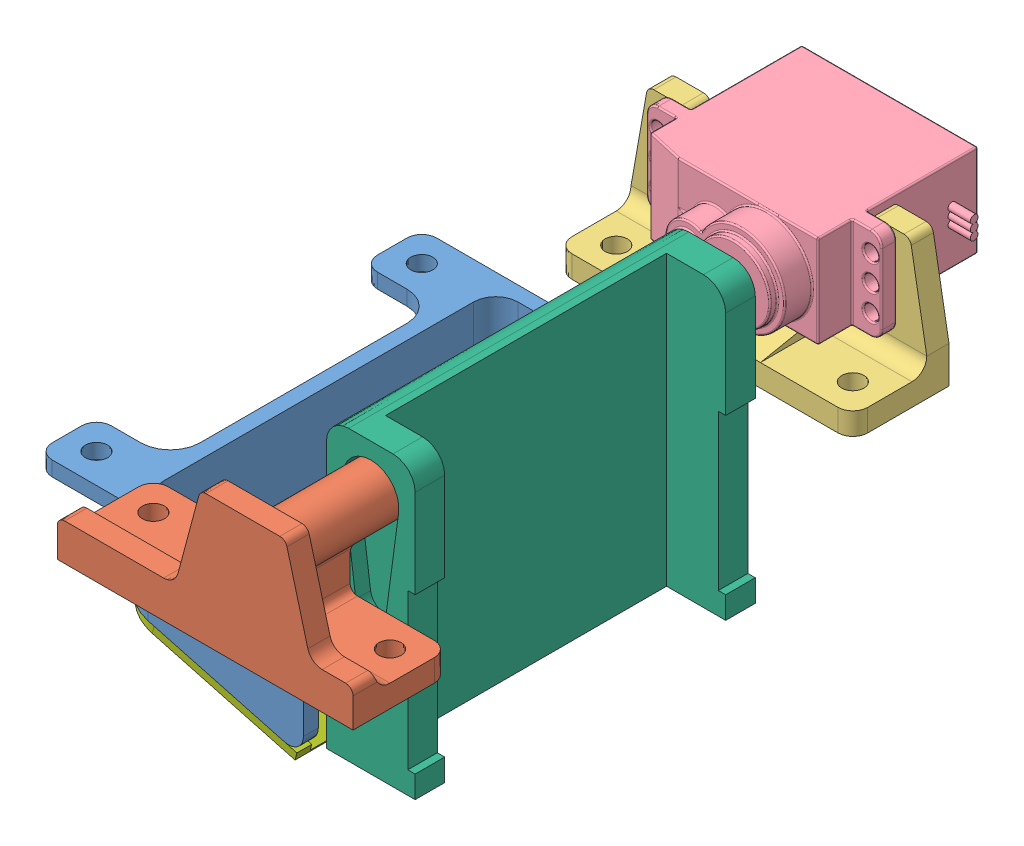
SolidWorks assembly Capture Mechanism Assy, configuration Default. Lengths in mm.
Overall size (57 39.73 92.6).
7 component instances, 7 part files, 16 mates.
Components (placement in the parent):
- Bucket-2: Bucket [Default] at origin size (36 17.39 52)
- Trapdoor Clevis-3: Trapdoor Clevis [Default] at (-7 32.75 37.3) x (-1 0 0) z (0 0 1) size (40 17.75 19)
- Servo Clevis-4: Servo Clevis [Default] at (-7 32.75 -37.3) x (1 0 0) z (0 0 -1) size (40 17.75 13)
- SM-S2309S Servo-3: SM-S2309S Servo [Défaut] at (-7 39 -52.3) x (1 0 0) z (0 -1 0) size (31.8 29.3 12.5)
- Servo Attachment-4: Servo Attachment [Default] at (-1.9 32.75 -21) x (-1 0 0) z (0 0 -1) size (7 17.5 4)
- Trapdoor-4: Trapdoor [Default] at (-1.9 32.75 0) x (-1 0 0) z (0 0 -1) size (12 39 46)
- Bucket Ramp-1: Bucket Ramp [Default] at (-21.5724 3.1191 0) x (0.965926 -0.258819 0) z (0 0 1) size (26 1 52)
Mates (geometry in assembly coordinates):
- Distance1: distance = 40.3 mm anti-aligned: plane of Servo Clevis-4 through (9.9127 37.75 -40.3) normal (0 0 -1)
- Distance2: distance = 3 mm anti-aligned: plane of Servo Clevis-4 through (-27 21 -40.3) normal (0 -1 0); plane of Bucket-2 through (-29 18 -21) normal (0 1 0)
- Distance3: distance = 40.3 mm aligned: plane of Trapdoor Clevis-3 through (-6.9 37.75 40.3) normal (0 0 1)
- Distance4: distance = 3 mm anti-aligned: plane of Trapdoor Clevis-3 through (13 21 40.3) normal (0 -1 0); plane of Bucket-2 through (-29 18 -21) normal (0 1 0)
- Coincident5: coincident aligned: plane of Trapdoor Clevis-3 through (13 25 40.3) normal (1 0 0); plane of Servo Clevis-4 through (13 26 -40.3) normal (1 0 0)
- Concentric1: concentric aligned: cylinder of Servo Clevis-4 through (7.4 32.75 -40.3) axis (0 0 1) radius 1; cylinder of SM-S2309S Servo-3 through (7.4 32.75 -52.301) axis (0 0 1) radius 1
- Concentric2: concentric aligned: cylinder of Servo Clevis-4 through (-21.4 32.75 -40.3) axis (0 0 1) radius 1; cylinder of SM-S2309S Servo-3 through (-21.4 32.75 -52.301) axis (0 0 1) radius 1
- Coincident6: coincident anti-aligned: plane of Servo Clevis-4 through (9.9127 37.75 -37.3) normal (0 0 1); plane of SM-S2309S Servo-3 through (-18.9 26.5 -37.3) normal (0 0 -1)
- Concentric4: concentric anti-aligned: cylinder of Servo Attachment-4 through (-1.9 32.75 -23) axis (0 0 1) radius 3.5; cylinder of Trapdoor-4 through (-1.9 32.75 -21) axis (0 0 -1) radius 3.8
- Coincident7: coincident anti-aligned: plane of Servo Attachment-4 through (-1.9 32.75 -21) normal (0 0 1); plane of Trapdoor-4 through (-1.9 32.75 -21) normal (0 0 -1)
- Coincident8: coincident anti-aligned: plane of Bucket-2 through (0 0 0) normal (0 0 1); plane of Trapdoor-4 through (-1.9 32.75 0) normal (0 0 -1)
- Concentric5: concentric anti-aligned: cylinder of SM-S2309S Servo-3 through (-1.9 32.75 -30.7) axis (0 0 -1) radius 2.4; cylinder of Servo Attachment-4 through (-1.9 32.75 -25) axis (0 0 1) radius 2.5
- Distance6: distance = 57 mm anti-aligned: plane of Bucket-2 through (-44 16 -26) normal (-1 0 0); plane of Servo Clevis-4 through (13 26 -40.3) normal (1 0 0)
- Coincident9: coincident anti-aligned: plane of Bucket-2 through (-8 0 -26) normal (-0.258819 -0.965926 0); plane of Bucket Ramp-1 through (-28.2044 5.4138 -20) normal (0.258819 0.965926 0)
- Width1: width anti-aligned: plane of Bucket Ramp-1 through (-28.2044 5.4138 26) normal (0 0 1); plane of Bucket-2 through (-28.2044 5.4138 -26) normal (0 0 -1); plane of Bucket Ramp-1 through (-8 18 -26) normal (0 0 -1); plane of Bucket-2 through (-29 18 26) normal (0 0 1)
- Coincident10: coincident aligned: line of Bucket-2 through (-34 6.9667 -21) axis (0 0 1); line of Bucket Ramp-1 through (-34 6.9667 -20) axis (0 0 1)
